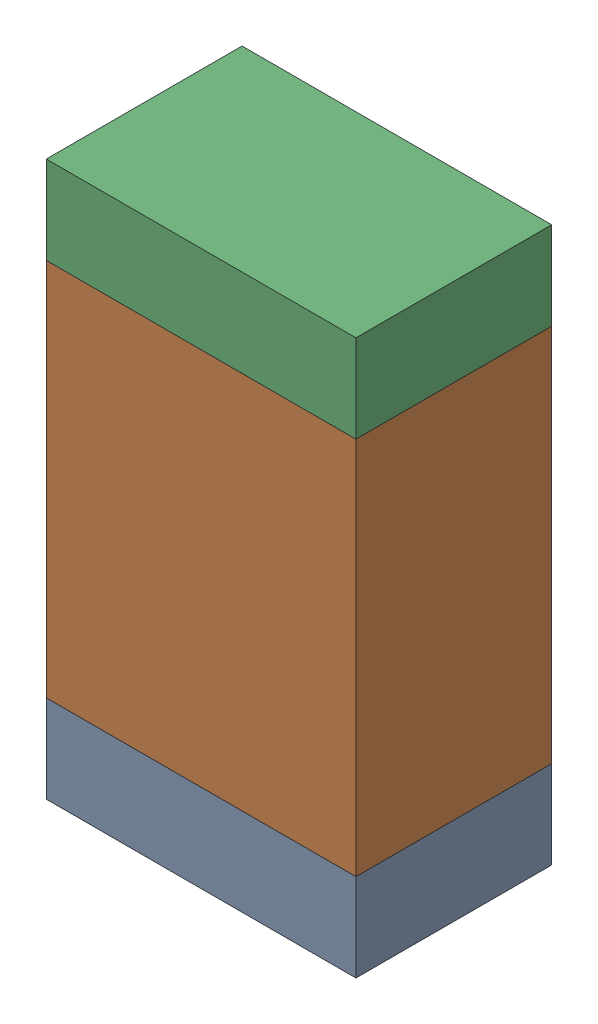
SolidWorks assembly R5-2, configuration Default. Lengths in mm.
Overall size (0.95 1.7 0.6).
6 component instances, 2 part files, 0 mates.
Components (placement in the parent):
- 959206216-2-1: 959206216-2 [Default] at (120.9041 81.6699 0) size (0.95 0.27 0.6)
  - Extruded-62-1: Extruded-62 [Default] at origin size (0.95 0.27 0.6)
- 959206352-2-1: 959206352-2 [Default] at (120.9041 82.3849 0) size (0.95 1.16 0.6)
  - Extruded-63-1: Extruded-63 [Default] at origin size (0.95 1.16 0.6)
- 959206216-2-2: 959206216-2 [Default] at (120.9041 83.0999 0) size (0.95 0.27 0.6)
  - Extruded-62-1: Extruded-62 [Default] at origin size (0.95 0.27 0.6)
